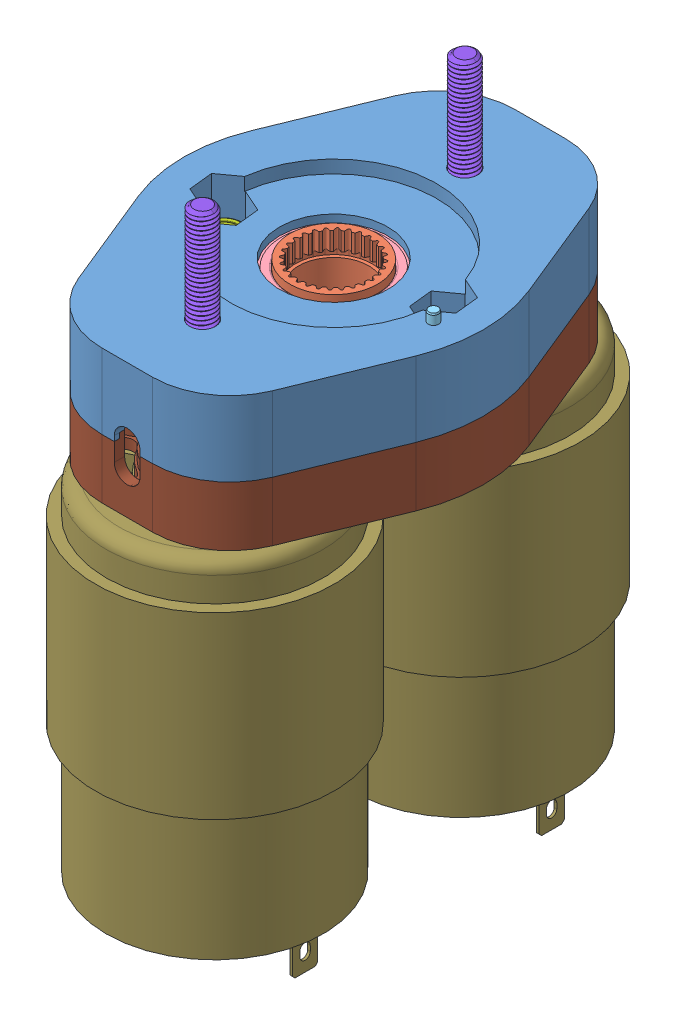
SolidWorks assembly VersaPlanetary Dual Input(775), configuration Default. Lengths in mm.
Overall size (58 53.23 80).
24 component instances, 13 part files, 0 mates.
Components (placement in the parent):
- 217-3141-001 Rev1-1: 217-3141-001 Rev1 [Default] x (0 0 1) z (-1 0 0) size (80 14.5 58)
- 217-3141-007 Rev1_30T 32DP-1: 217-3141-007 Rev1_30T 32DP [Default] at (0 -7.06 0) x (0 -1 0) z (-0.999183 0 0.040426) size (22.38 25.55 25.47)
- 217-3141-006 Rev1_30T 32DP-1: 217-3141-006 Rev1_30T 32DP [Default] at (0.8337 -9.0499 -23.8741) x (-0.095925 0 -0.995389) z (0 -1 0) size (25.47 25.55 10)
- 217-3141-006 Rev1_30T 32DP-2: 217-3141-006 Rev1_30T 32DP [Default] at (0.8337 -9.0499 23.8741) x (-0.001725 0 0.999999) z (0 -1 0) size (25.47 25.55 10)
- 217-2741-1: 217-2741 [Default] at (0 2.75 0) x (0 -1 0) z (-0.999445 0 -0.033298) size (5 26 26)
- 217-2741-2: 217-2741 [Default] at (0 -13.25 0) x (0 -1 0) z (-0.537831 0 0.843053) size (5 26 26)
- PINL-M020-006-S-1: PINL-M020-006-S [Default] at (22.7445 5.75 3.4184) x (0 1 0) z (-0.890225 0 0.455522) size (6 2 2)
- SSS1032-0188-ZB-1: SSS1032-0188-ZB [Default] at (0.4848 -10.9249 -27.4949) x (-0.758755 -0.647259 0.073121) z (0.095925 0 0.995389) size (4.91 4.91 5.06)
- SSS1032-0188-ZB-2: SSS1032-0188-ZB [Default] at (0.8274 -10.9249 27.5116) x (0.762269 -0.647259 0.001315) z (0.001725 0 -0.999999) size (4.91 4.91 5.06)
- NUT-832-NYLOCK-1: NUT-832-NYLOCK [Default] at (19.244 -4.75 -2.0226) x (0.913545 0 0.406737) z (-0.406737 0 0.913545) size (10.2 4.9 8.12)
- NUT-832-NYLOCK-2: NUT-832-NYLOCK [Default] at (-19.244 -4.75 2.0226) x (0.912648 0 0.408747) z (-0.408747 0 0.912648) size (10.2 4.9 8.12)
- 91251A346_91251A346-1: 91251A346_91251A346 [Default] at (0 25.975 25.4) x (1 0 0) z (0 1 0) size (7.92 7.92 27.28)
- 91251A346_91251A346-2: 91251A346_91251A346 [Default] at (0 25.975 -25.4) x (1 0 0) z (0 1 0) size (7.92 7.92 27.28)
- SSA_SSAM4-0010ZC-1: SSA_SSAM4-0010ZC [Default] at (12.5 -17.25 -23.8887) size (7 14 7)
- SSA_SSA0832-0750ZC-1: SSA_SSA0832-0750ZC [Default] at (19.244 -19.2499 -2.0226) x (-0.091926 0 -0.995766) z (-0.995766 0 0.091926) size (6.73 23.11 6.73)
- SSA_SSA0832-0750ZC-2: SSA_SSA0832-0750ZC [Default] at (-19.244 -19.2499 2.0226) x (-0.18632 0 -0.982489) z (-0.982489 0 0.18632) size (6.73 23.11 6.73)
- SSA_SSAM4-0010ZC-2: SSA_SSAM4-0010ZC [Default] at (-13.6663 -17.2499 23.8741) x (0.677756 0 0.735287) z (-0.735287 0 0.677756) size (7 14 7)
- SSA_SSAM4-0010ZC-3: SSA_SSAM4-0010ZC [Default] at (15.3337 -17.2499 23.8741) x (0.994338 0 -0.106265) z (0.106265 0 0.994338) size (7 14 7)
- SSA_SSAM4-0010ZC-4: SSA_SSAM4-0010ZC [Default] at (-13.6663 -17.2499 -23.8741) x (0.537906 0 -0.843005) z (0.843005 0 0.537906) size (7 14 7)
- 217-3141-004 Rev1-1: 217-3141-004 Rev1 [Default] at (0 -12.9999 0) x (0 0 1) z (0 1 0) size (80 58 12.5)
- BB RS775-18V-1: BB RS775-18V [Default] at (0.8337 -19.2499 23.8741) x (0 -1 0) z (0 0 1)
- BB RS775-18V-2: BB RS775-18V [Default] at (0.8337 -19.2499 -23.8741) x (0 -1 0) z (0 0 -1)
- 217-2625-013 Rev1-1: 217-2625-013 Rev1 [Default] at (0.8337 -10.1999 23.8741) x (1 0 0) z (0 1 0) size (8 7.93 7.5)
- 217-2625-013 Rev1-2: 217-2625-013 Rev1 [Default] at (0.8337 -10.1999 -23.8741) x (1 0 0) z (0 1 0) size (8 7.93 7.5)
